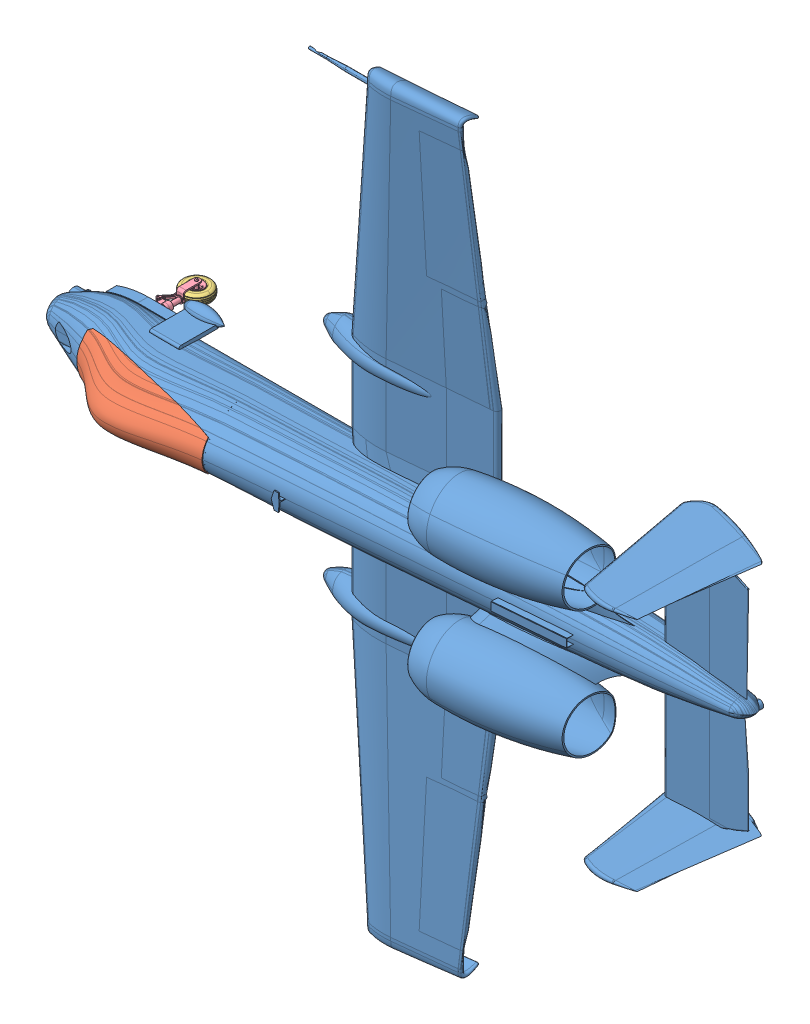
SolidWorks assembly Complete A-10 reference, configuration Default. Lengths in mm.
Overall size (2372.64 2478.71 696.61).
11 component instances, 8 part files, 0 mates.
Components (placement in the parent):
- Body-1: Body [Default] at origin size (2372.64 2478.71 495.27)
- Cockpit-1: Cockpit [Default] at origin size (495.66 194.74 196)
- Nose gear assembly-1: Nose gear assembly [Default] at (247.345 48.7419 -200.4844) x (-1 0 0) z (0 0 1) size (141.49 51.46 239.99)
  - Nose gear tire-1: Nose gear tire [Default] at origin size (94.36 34.37 94.36)
  - Nose gear-1: Nose gear [Default] at origin size (139.9 51.46 216.43)
- Landing gear assembly-1: Landing gear assembly [Default] at (970.4875 -474.5931 -361.989) size (137.21 80.09 297.16)
  - Landing gear tire-1: Landing gear tire [Default] at (41.2481 74.6537 108.5035) size (137.21 51.51 137.21)
  - Langing gear-1: Langing gear [Default] at (41.1897 73.9625 108.2807) size (107.12 80.09 265.25)
- MirrorLanding gear assembly-3: MirrorLanding gear assembly [Default] at (970.4875 474.5931 -361.989) x (1 0 0) z (0 0 -1) size (137.21 80.09 297.16)
  - MirrorLanding gear tire-1: MirrorLanding gear tire [Default] at (41.2481 74.6537 -108.5035) size (137.21 51.51 137.21)
  - MirrorLanging gear-1: MirrorLanging gear [Default] at (41.1897 73.9625 -108.2807) size (107.12 80.09 265.25)
